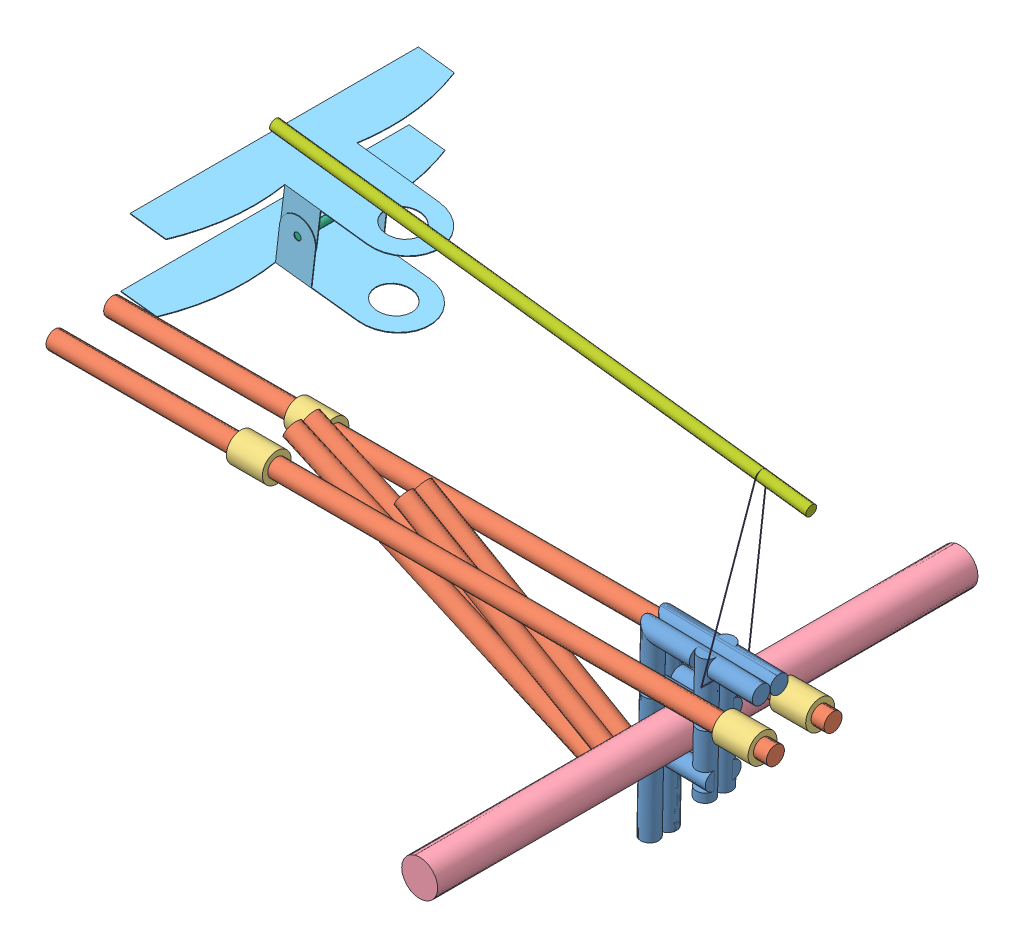
SolidWorks assembly 发射装置01, configuration 默认. Lengths in mm.
Overall size (201.73 118.1 150).
12 component instances, 8 part files, 18 mates.
Components (placement in the parent):
- 扳机-1: 扳机 [默认] at (-76.7516 7.0814 3) x (-0.999796 0.020174 0) z (0 0 -1) size (32.5 52.5 10.01)
- 触动杆-2: 触动杆 [默认] at (26.1004 16.8941 0) x (-1 0 0) z (0 0 1) size (200 44.52 21)
- 套-1: 套 [默认] at (-58.1682 16.8941 8.3916) x (1 0 0) z (0 0.047885 0.998853) size (10 8 8)
- 套-2: 套 [默认] at (-58.1682 16.8941 -7.6084) x (1 0 0) z (0 -0.99254 -0.121918) size (10 8 8)
- 粗杆20x15-1: 粗杆20x15 [默认] at (-76.802 4.5819 -75.0735) size (10 10 150)
- 套-3: 套 [默认] at (-193.0032 16.8941 8.3916) size (10 8 8)
- 套-4: 套 [默认] at (-193.0032 16.8941 -7.6084) x (1 0 0) z (0 -0.85731 0.5148) size (10 8 8)
- 夹子01-1: 夹子01 [默认] at (-158.7118 65.2013 0.2) x (0 0 1) z (-0.993299 0.115576 0) size (80 15 46)
- 夹子杆-1: 夹子杆 [默认] at (-175.4469 77.1153 0) x (0.923728 0.383049 0) z (0 0 1) size (2 2 20)
- 夹子01-2: 夹子01 [默认] at (-156.3652 84.7244 0) x (0 0 -1) z (-0.992395 0.123092 0) size (80 15 46)
- 细杆150x1.5-1: 细杆150x1.5 [默认] at (-165.7698 92.3264 0) x (0.992395 -0.123092 0) z (0 0 1) size (150 3 3)
- 绳-1: 绳 [默认] at (36.1096 -19.4577 1.1514) x (0.984358 -0.17618 -0.00047) z (0.003297 0.015752 0.99987) size (0.2 54.67 13.2)
Mates (geometry in assembly coordinates):
- 同心1: concentric aligned: cylinder of 触动杆-2 through (-44.576 16.8941 -7.6084) axis (-1 0 0) radius 2.5; cylinder of 套-2 through (-48.1682 16.8941 -7.6084) axis (-1 0 0) radius 2.5
- 同心2: concentric aligned: cylinder of 触动杆-2 through (-244.576 16.8941 8.3916) axis (-1 0 0) radius 2.5; cylinder of 套-1 through (-48.1682 16.8941 8.3916) axis (-1 0 0) radius 2.5
- 重合1: coincident aligned: plane of 套-1 through (-48.1682 16.8941 8.3916) normal (1 0 0); plane of 套-2 through (-48.1682 16.8941 -7.6084) normal (1 0 0)
- 相切1: tangent anti-aligned: cylinder of 粗杆20x15-1 through (-76.802 4.5819 74.9265) axis (0 0 -1) radius 5; cylinder of 扳机-1 through (-68.9505 21.927 3) axis (0.020174 0.999796 0) radius 2.5
- 距离4: distance = 22.5 mm aligned: line of 粗杆20x15-1 through (-76.802 4.5819 74.9265) axis (0 0 -1); plane of 扳机-1
- 同心5: concentric aligned: cylinder of 套-4 through (-183.0032 16.8941 -7.6084) axis (-1 0 0) radius 2.5; cylinder of 触动杆-2 through (-44.576 16.8941 -7.6084) axis (-1 0 0) radius 2.5
- 同心6: concentric aligned: cylinder of 触动杆-2 through (-244.576 16.8941 8.3916) axis (-1 0 0) radius 2.5; cylinder of 套-3 through (-183.0032 16.8941 8.3916) axis (-1 0 0) radius 2.5
- 重合6: coincident aligned: plane of 套-3 through (-193.0032 16.8941 8.3916) normal (-1 0 0); plane of 套-4 through (-193.0032 16.8941 -7.6084) normal (-1 0 0)
- 同心7: concentric anti-aligned: cylinder of 夹子01-1 through (-175.4469 77.1153 10) axis (0 0 1) radius 1; cylinder of 夹子01-2 through (-175.4469 77.1153 -9.8) axis (0 0 -1) radius 1
- 重合8: coincident anti-aligned: plane of 夹子01-1 through (-175.4469 77.1153 10) normal (0 0 -1); plane of 夹子01-2 through (-156.3775 84.6251 10) normal (0 0 1)
- 同心8: concentric anti-aligned: cylinder of 夹子01-1 through (-175.4469 77.1153 10) axis (0 0 1) radius 1; cylinder of 夹子杆-1 through (-175.4469 77.1153 10) axis (0 0 -1) radius 1
- 重合9: coincident aligned: plane of 夹子杆-1 through (-175.4469 77.1153 -10) normal (0 0 -1); plane of 夹子01-2 through (-156.3775 84.6251 -10) normal (0 0 -1)
- 重合10: coincident anti-aligned: plane of 触动杆-2 through (26.1004 16.8941 0) normal (0 0 1); plane of 夹子01-2
- 重合11: coincident anti-aligned: plane of 夹子01-2; plane of 细杆150x1.5-1 through (-165.7698 92.3264 0) normal (0 0 1)
- 相切2: tangent anti-aligned: plane of 夹子01-2 through (-156.3529 84.8236 0) normal (0.123092 0.992395 0); cylinder of 细杆150x1.5-1 through (-191.8945 90.7435 0) axis (-0.992395 0.123092 0) radius 1.5
- 重合12: coincident aligned: plane of 夹子01-2 through (-192.1038 89.0565 -40) normal (-0.992395 0.123092 0); plane of 细杆150x1.5-1 through (-191.8945 90.7435 0) normal (-0.992395 0.123092 0)
- 相切3: tangent: cylinder of 细杆150x1.5-1 through (-191.8945 90.7435 0) axis (-0.992395 0.123092 0) radius 1.5; face of 绳-1
- 距离5: distance = 3 mm anti-aligned: plane of 扳机-1 through (-76.7516 7.0814 3) normal (0 0 -1); plane of 触动杆-2 through (26.1004 16.8941 0) normal (0 0 1)
